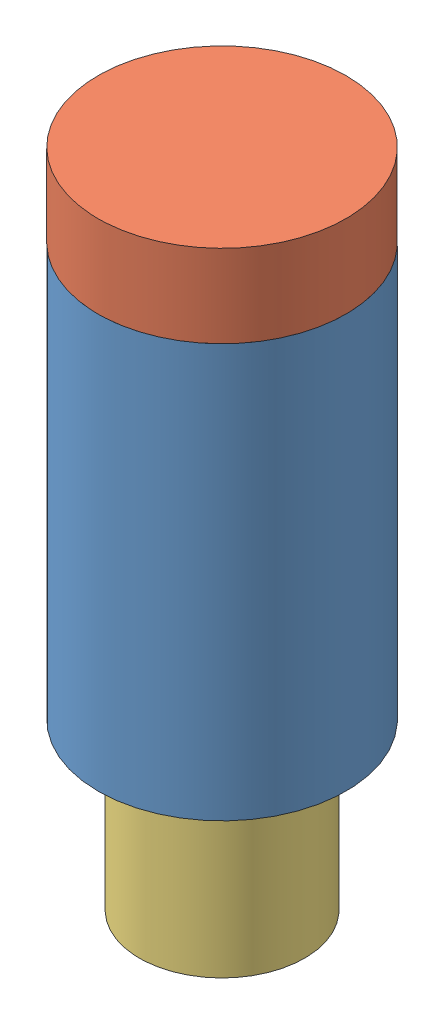
SolidWorks assembly S1B_Recovery_System_Representation, configuration Default. Lengths in mm.
Overall size (76.2 203.2 76.2).
3 component instances, 3 part files, 6 mates.
Components (placement in the parent):
- S1B_Main_Parachute_REPRESENTATION-1: S1B_Main_Parachute_REPRESENTATION [Default] at origin size (76.2 127 76.2)
- S1B_Drogue_Parachute_REPRESENTATION-1: S1B_Drogue_Parachute_REPRESENTATION [Default] at (0 127 0) size (76.2 25.4 76.2)
- S1B_Shock_Cord_and_Quick_Links_REPRESENTATION-1: S1B_Shock_Cord_and_Quick_Links_REPRESENTATION [Default] at (0 -50.8 0) size (50.8 101.6 50.8)
Mates (geometry in assembly coordinates):
- Coincident1: coincident anti-aligned: plane of S1B_Main_Parachute_REPRESENTATION-1 through (0 127 0) normal (0 1 0); plane of S1B_Drogue_Parachute_REPRESENTATION-1 through (0 127 0) normal (0 -1 0)
- Coincident2: coincident anti-aligned: line of S1B_Drogue_Parachute_REPRESENTATION-1 through (27.94 0 125.73) axis (0 0 1)
- Distance1: distance = 50.8 mm aligned: plane of S1B_Shock_Cord_REPRESENTATION-1 through (0 -50.8 0) normal (0 -1 0); plane of S1B_Main_Parachute_REPRESENTATION-1 through (0 0 0) normal (0 -1 0)
- Coincident3: coincident anti-aligned: line of S1B_Shock_Cord_REPRESENTATION-1 through (111.76 0 -55.88) axis (0 0 1)
- Parallel1: parallel aligned: plane of S1B_Drogue_Parachute_REPRESENTATION-1 through (0 127 0) normal (0 0 1)
- Parallel2: parallel aligned: plane of S1B_Shock_Cord_and_Quick_Links_REPRESENTATION-1 through (0 -50.8 0) normal (0 0 1)
